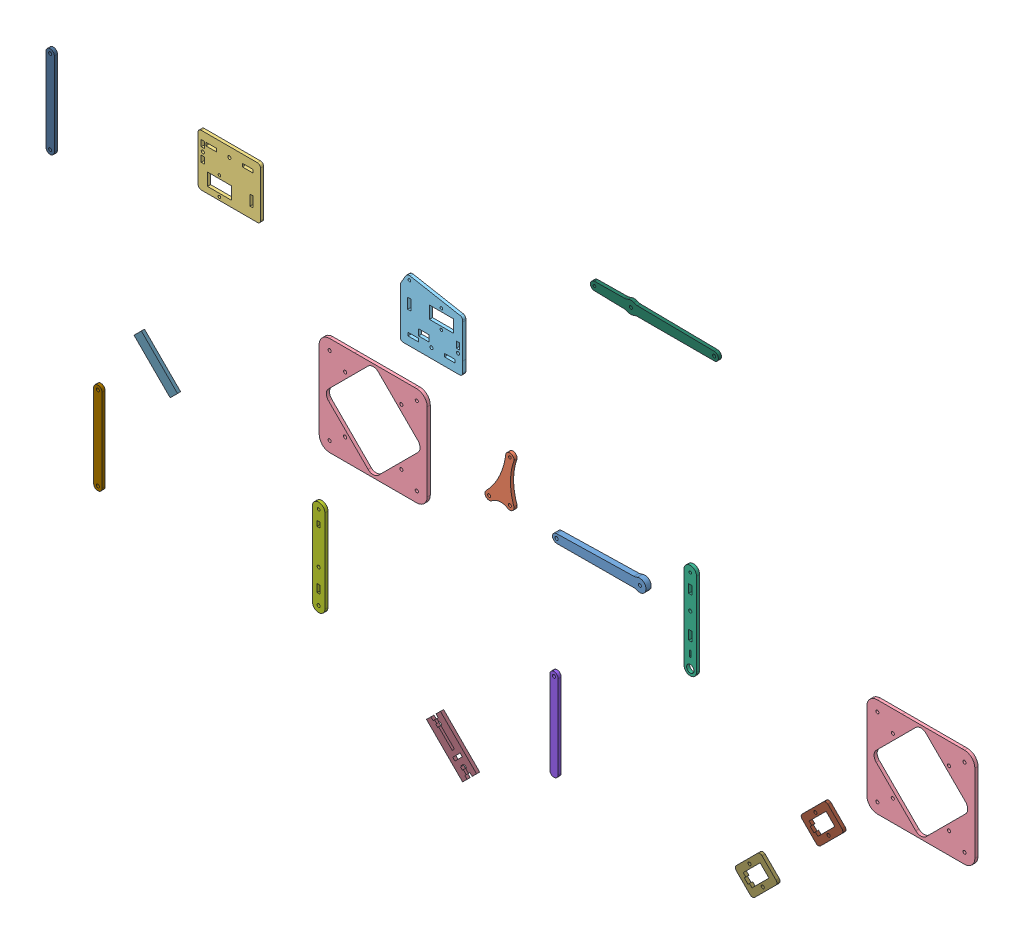
SolidWorks assembly 組合件1, configuration 預設. Lengths in mm.
Overall size (973.05 482.14 88.83).
16 component instances, 15 part files, 0 mates.
Components (placement in the parent):
- 1-1: 1 [預設] at (-2222.0362 -1624.9659 87.3486) size (89.85 12 5)
- 2-1: 2 [預設] at (-2283.6303 -1567.634 90.8486) size (27.93 49.47 3)
- 3-1: 3 [預設] at (-2585.6102 -1447.9831 92.3486) size (60 49.7 3)
- 10-1: 10 [預設] at (-2486.9203 -1511.1199 90.9898) size (103.75 95 3)
- 4-1: 4 [預設] at (-2449.9367 -1476.2166 93.8486) size (60.03 58.61 3)
- 5-1: 5 [預設] at (-2088.6745 -1525.1656 90.8486) size (12 92 3)
- 6-1: 6 [預設] at (-2456.0927 -1648.195 92.3486) size (12 92 3)
- 7-1: 7 [預設] at (-2240.0953 -1672.1328 92.3486) size (8 88 3)
- 8-1: 8 [預設] at (-2683.2239 -1649.8651 95.3486) size (8 88 3)
- 9-1: 9 [預設] at (-2740.0067 -1396.0125 92.3486) size (8 88 3)
- 10-2: 10 [預設] at (-1878.6617 -1466.5214 173.1743) size (103.75 95 3)
- 11-1: 11 [預設] at (-2035.8271 -1625.0786 92.3486) size (39.94 39.94 3)
- 12-1: 12 [預設] at (-2115.3106 -1680.4103 93.8486) size (39.94 39.94 3)
- 13-1: 13 [預設] at (-2418.1656 -1747.4985 93.8486) size (48.14 48.14 3)
- 14-1: 14 [預設] at (-2709.5198 -1578.8197 96.8486) size (41.78 41.78 3)
- 15-1: 15 [預設] at (-2337.6598 -1394.1676 94.3486) size (123.02 12 3)
